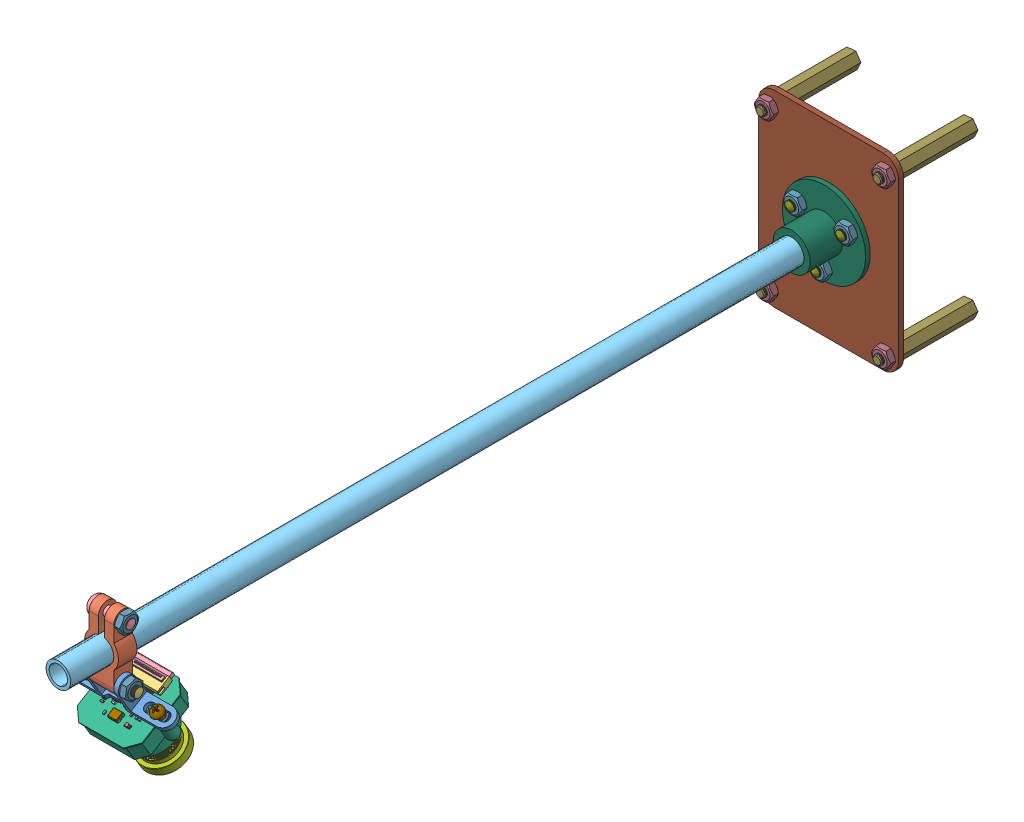
SolidWorks assembly 摄像头装配体, configuration 默认. Lengths in mm.
Overall size (45.45 73.53 276.6).
90 component instances, 34 part files, 64 mates.
Components (placement in the parent):
- 摄像头固定夹-1: 摄像头固定夹 [默认] at (-73.5266 8.9019 124.6716) x (1 0 0) z (0 -0.51597 0.856607) size (34 11.5 6)
- 摄像头支架-1: 摄像头支架 [默认] at (-73.5266 23.6352 128.6271) x (0 -1 0) z (0 0 1) size (24 11 6)
- 十字半圆头长螺钉-M3-白色-16MM-1: 十字半圆头长螺钉-M3-白色-16MM [GB_WOOD_SCREWS_TYPE136 M3X8-N] at (-81.3966 14.6352 131.6271) size (17.31 5.8 5.8)
- 十字半圆头长螺钉-M3-白色-2: 十字半圆头长螺钉-M3-白色 [GB_WOOD_SCREWS_TYPE136 M3X8-N] at (-79.8966 32.6352 131.6271) size (13.31 5.8 5.8)
- 碳纤维杆-摄像头主桅-1: 碳纤维杆-摄像头主桅 [默认] at (-73.5266 23.6352 -101.3729) size (8 8 250)
- 摄像头-1: 摄像头 [Default] at (-73.0566 5.2928 126.029) x (1 0 0) z (0 -0.856607 -0.51597) size (26.62 21 25.09)
  - Board摄像头-1: Board摄像头 [默认] at (0 0 -0.3912) size (26.62 21 0.39)
  - Y1摄像头-1: Y1摄像头 [默认] at origin size (3.3 2.6 1.1)
    - XTAL-OSC-3225-1: XTAL-OSC-3225 [默认] at (0.2033 4.7751 -0.3912) x (1 0 0) z (0 0 -1) size (3.3 2.6 1.1)
      - User_Library-ASTX-H11_Pad-1: User_Library-ASTX-H11_Pad [默认] at origin size (3.3 2.6 0.8)
      - User_Library-ASTX-H11_Pad001-1: User_Library-ASTX-H11_Pad001 [默认] at origin size (2.8 2.4 0.24)
      - User_Library-ASTX-H11_Pad002-1: User_Library-ASTX-H11_Pad002 [默认] at origin size (2.7 2.3 0.04)
      - User_Library-ASTX-H11_ComponentPads-1: User_Library-ASTX-H11_ComponentPads [默认] at origin size (3.3 2.59 0.4)
  - U2摄像头-1: U2摄像头 [默认] at origin size (2.8 2.9 1.45)
    - SOT23-5-1: SOT23-5 [默认] at (-2.517 0.4825 -0.3912) x (0 1 0) z (0 0 -1) size (2.9 2.8 1.45)
  - U1摄像头-1: U1摄像头 [默认] at origin size (11.45 11.44 2.21)
    - CLCC-48-11.43x11.43mm-1: CLCC-48-11.43x11.43mm [默认] at (-0.0237 0.0119 0) x (-1 0 0) z (0 0 1) size (11.45 11.44 2.21)
  - R4摄像头-1: R4摄像头 [默认] at origin size (1 0.5 0.36)
    - RES-0402-1: RES-0402 [默认] at (-5.6286 2.5399 -0.5612) x (0 -1 0) z (1 0 0) size (0.5 0.36 1)
  - R3摄像头-1: R3摄像头 [默认] at origin size (1 0.5 0.36)
    - RES-0402-1: RES-0402 [默认] at (-5.6286 3.4543 -0.5612) x (0 -1 0) z (1 0 0) size (0.5 0.36 1)
  - R2摄像头-1: R2摄像头 [默认] at origin size (0.5 1 0.36)
    - RES-0402-1: RES-0402 [默认] at (3.4035 2.7072 -0.5612) x (-1 0 0) z (0 -1 0) size (0.5 0.36 1)
  - R1摄像头-1: R1摄像头 [默认] at origin size (1 0.5 0.36)
    - RES-0402-1: RES-0402 [默认] at (5.5524 -2.6923 -0.5612) x (0 1 0) z (-1 0 0) size (0.5 0.36 1)
  - L2摄像头-1: L2摄像头 [默认] at origin size (1 0.6 0.5)
    - Chip_Inductor-0402_100505-1: Chip_Inductor-0402_100505 [默认] at (2.7686 0.7112 -0.6312) x (1 0 0) z (0 0 -1) size (1 0.6 0.5)
  - L1摄像头-1: L1摄像头 [默认] at origin size (1 0.6 0.5)
    - Chip_Inductor-0402_100505-1: Chip_Inductor-0402_100505 [默认] at (2.7686 -0.1778 -0.6312) x (1 0 0) z (0 0 -1) size (1 0.6 0.5)
  - D1摄像头-1: D1摄像头 [默认] at origin size (1.7 0.9 0.9)
    - LED-BLUE-0603-1: LED-BLUE-0603 [默认] at (4.4957 5.5045 -0.3912) x (0 1 0) z (0 0 -1) size (0.9 1.7 0.9)
      - User_Library-LTST-C190TBKT_Pad-1: User_Library-LTST-C190TBKT_Pad [默认] at origin size (0.9 1.7 0.28)
      - User_Library-LTST-C190TBKT_Pad005-1: User_Library-LTST-C190TBKT_Pad005 [默认] at origin size (0.35 0.15 0.31)
      - User_Library-LTST-C190TBKT_Pad001-1: User_Library-LTST-C190TBKT_Pad001 [默认] at origin size (0.9 1.7 0.01)
      - User_Library-LTST-C190TBKT_Pad004-1: User_Library-LTST-C190TBKT_Pad004 [默认] at origin size (0.35 0.15 0.31)
      - User_Library-LTST-C190TBKT_Pad003-1: User_Library-LTST-C190TBKT_Pad003 [默认] at origin size (0.8 1.7 0.02)
      - User_Library-LTST-C190TBKT_Lens-1: User_Library-LTST-C190TBKT_Lens [默认] at origin size (0.9 1.15 0.6)
  - CN1摄像头-1: CN1摄像头 [默认] at origin size (13.1 6.5 2.25)
    - FPC-ZIF-SMD-Horizontal-0.5-18-1: FPC-ZIF-SMD-Horizontal-0.5-18 [默认] at (-0.0001 -9.0679 -0.3912) x (-1 0 0) z (0 -1 0) size (13.1 2.25 5.2)
    - FPC-ZIF-SMD-Horizontal-0.5-18_2-1: FPC-ZIF-SMD-Horizontal-0.5-18_2 [默认] at (-0.0001 -9.0679 -0.3912) x (-1 0 0) z (0 -1 0) size (13.1 1.2 2.95)
  - C11摄像头-1: C11摄像头 [默认] at origin size (0.5 1 0.5)
    - CAP-0402-1: CAP-0402 [默认] at (-0.1015 0.0381 -0.6312) x (0 -1 0) z (1 0 0) size (1 0.5 0.5)
  - C10摄像头-1: C10摄像头 [默认] at origin size (1 0.5 0.5)
    - CAP-0402-1: CAP-0402 [默认] at (-2.7305 2.6923 -0.6312) x (-1 0 0) z (0 -1 0) size (1 0.5 0.5)
  - C9摄像头-1: C9摄像头 [默认] at origin size (0.5 1 0.5)
    - CAP-0402-1: CAP-0402 [默认] at (5.8421 -0.0889 -0.6312) x (0 -1 0) z (1 0 0) size (1 0.5 0.5)
  - C8摄像头-1: C8摄像头 [默认] at origin size (0.5 1 0.5)
    - CAP-0402-1: CAP-0402 [默认] at (4.8261 -0.0889 -0.6312) x (0 -1 0) z (1 0 0) size (1 0.5 0.5)
  - C7摄像头-1: C7摄像头 [默认] at origin size (0.5 1 0.5)
    - CAP-0402-1: CAP-0402 [默认] at (0.8383 0.0381 -0.6312) x (0 -1 0) z (1 0 0) size (1 0.5 0.5)
  - C6摄像头-1: C6摄像头 [默认] at origin size (0.5 1 0.5)
    - CAP-0402-1: CAP-0402 [默认] at (-2.7687 5.4737 -0.6312) x (0 1 0) z (-1 0 0) size (1 0.5 0.5)
  - C5摄像头-1: C5摄像头 [默认] at origin size (1 0.5 0.5)
    - CAP-0402-1: CAP-0402 [默认] at (5.5655 -1.5241 -0.6312) x (-1 0 0) z (0 -1 0) size (1 0.5 0.5)
  - C4摄像头-1: C4摄像头 [默认] at origin size (1 0.5 0.5)
    - CAP-0402-1: CAP-0402 [默认] at (0.6731 1.5495 -0.6312) x (1 0 0) z (0 1 0) size (1 0.5 0.5)
  - C3摄像头-1: C3摄像头 [默认] at origin size (0.5 1 0.5)
    - CAP-0402-1: CAP-0402 [默认] at (5.3339 2.6637 -0.6312) x (0 1 0) z (-1 0 0) size (1 0.5 0.5)
  - C2摄像头-1: C2摄像头 [默认] at origin size (0.5 1 0.5)
    - CAP-0402-1: CAP-0402 [默认] at (-5.5373 -0.4445 -0.6312) x (0 1 0) z (-1 0 0) size (1 0.5 0.5)
  - C1摄像头-1: C1摄像头 [默认] at origin size (0.5 1 0.5)
    - CAP-0402-1: CAP-0402 [默认] at (5.8421 2.6543 -0.6312) x (0 -1 0) z (1 0 0) size (1 0.5 0.5)
  - 摄像头-1-1: 摄像头-1 [默认] at (3.1459 -0.8951 -20.4725) size (26.25 20.05 22.5)
    - 底座-1: 底座 [默认] at (-3.1409 0.8701 20.4725) size (26.25 20.05 13.15)
    - 镜头-1: 镜头 [默认] at (-3.1409 0.8701 39.9725) x (0.192959 -0.981207 0) z (0 0 -1) size (14 14 15.3)
    - 螺钉-1: 螺钉 [ISO 7047 - M1.6 x 3 - Z --- 3N] at (-3.1295 -8.8207 30.7429) x (-0.001176 0.999999 0) z (-0.196345 -0.000231 0.980535) size (3.37 3 3)
- 十字半圆头螺钉-M2-1: 十字半圆头螺钉-M2 [GB_WOOD_SCREWS_TYPE136 M2X8-N] at (-61.9266 10.0095 128.8409) x (0 -0.856607 -0.51597) z (1 0 0) size (6.56 3.9 3.9)
- 垫片-M3-1: 垫片-M3 [默认] at (-61.9266 5.6408 126.2095) x (0.716918 0.359712 -0.59719) z (0 0.856607 0.51597) size (4.5 4.5 1)
- 垫片-M3-2: 垫片-M3 [默认] at (-61.9266 7.354 127.2414) x (0.41754 -0.468841 0.778363) z (0 -0.856607 -0.51597) size (4.5 4.5 1)
- 垫片-M3-3: 垫片-M3 [默认] at (-84.1766 6.4974 126.7254) x (0.716918 0.359712 -0.59719) z (0 0.856607 0.51597) size (4.5 4.5 1)
- 十字半圆头螺钉-M2-2: 十字半圆头螺钉-M2 [GB_WOOD_SCREWS_TYPE136 M2X8-N] at (-84.1766 10.0095 128.8409) x (0 -0.856607 -0.51597) z (0.359414 -0.481492 0.799367) size (6.56 3.9 3.9)
- 垫片-M3-4: 垫片-M3 [默认] at (-84.1766 5.6408 126.2095) x (0.716918 0.359712 -0.59719) z (0 0.856607 0.51597) size (4.5 4.5 1)
- 摄像头固定底板-1: 摄像头固定底板 [默认] at (-73.5266 23.6352 -102.9729) x (-1 0 0) z (0 0 1) size (45.45 61 1.6)
- 铜柱_25MM-1: 铜柱_25MM [默认] at (-54.5266 49.1352 -127.9729) size (5.75 5.22 30.08)
- 铜柱_25MM-2: 铜柱_25MM [默认] at (-92.5266 49.1352 -127.9729) size (5.75 5.22 30.08)
- 铜柱_25MM-3: 铜柱_25MM [默认] at (-92.5266 -1.8648 -127.9729) size (5.75 5.22 30.08)
- 铜柱_25MM-4: 铜柱_25MM [默认] at (-54.5266 -1.8648 -127.9729) size (5.75 5.22 30.08)
- 六角螺母-M3-黄色-2: 六角螺母-M3-黄色 [GB_FASTENER_NUT_SNAB1 M3-C] at (-92.5266 49.1352 -98.9729) size (6.35 5.5 2.4)
- 六角螺母-M3-黄色-3: 六角螺母-M3-黄色 [GB_FASTENER_NUT_SNAB1 M3-C] at (-54.5266 49.1352 -98.9729) size (6.35 5.5 2.4)
- 六角螺母-M3-黄色-5: 六角螺母-M3-黄色 [GB_FASTENER_NUT_SNAB1 M3-C] at (-92.5266 -1.8648 -98.9729) size (6.35 5.5 2.4)
- 六角螺母-M3-黄色-6: 六角螺母-M3-黄色 [GB_FASTENER_NUT_SNAB1 M3-C] at (-54.5266 -1.8648 -98.9729) size (6.35 5.5 2.4)
- 六角螺母-M3-白色-6: 六角螺母-M3-白色 [GB_FASTENER_NUT_SNAB1 M3-C] at (-67.1266 32.6352 131.6271) x (0 0 -1) z (1 0 0) size (6.35 5.5 2.4)
- 六角螺母-M3-白色-7: 六角螺母-M3-白色 [GB_FASTENER_NUT_SNAB1 M3-C] at (-65.6266 14.6352 131.6271) x (0 -0.333114 0.942887) z (1 0 0) size (6.35 5.5 2.4)
- 摄像头固定底座-铝制-1: 摄像头固定底座-铝制 [默认] at (-73.5266 23.6352 -101.3729) x (0.5 0.866025 0) z (0 0 1) size (27 27 12)
- 十字半圆头螺钉-M3-白色-8: 十字半圆头螺钉-M3-白色 [GB_WOOD_SCREWS_TYPE136 M3X8-N] at (-65.2994 28.3852 -105.3429) x (0 0 1) z (-0.781973 0.623312 0) size (9.31 5.8 5.8)
- 十字半圆头螺钉-M3-白色-9: 十字半圆头螺钉-M3-白色 [GB_WOOD_SCREWS_TYPE136 M3X8-N] at (-81.7539 28.3852 -105.3429) x (0 0 1) z (-1 0 0) size (9.31 5.8 5.8)
- 十字半圆头螺钉-M3-白色-11: 十字半圆头螺钉-M3-白色 [GB_WOOD_SCREWS_TYPE136 M3X8-N] at (-73.5266 14.1352 -105.3429) x (0 0 1) z (-1 0 0) size (9.31 5.8 5.8)
- 六角螺母-M3-白色-14: 六角螺母-M3-白色 [GB_FASTENER_NUT_SNAB1 M3-C] at (-81.7539 28.3852 -97.4729) size (6.35 5.5 2.4)
- 六角螺母-M3-白色-15: 六角螺母-M3-白色 [GB_FASTENER_NUT_SNAB1 M3-C] at (-65.2994 28.3852 -97.4729) size (6.35 5.5 2.4)
- 六角螺母-M3-白色-16: 六角螺母-M3-白色 [GB_FASTENER_NUT_SNAB1 M3-C] at (-73.5266 14.1352 -97.4729) size (6.35 5.5 2.4)
Mates (geometry in assembly coordinates):
- 同心1: concentric anti-aligned: cylinder of 摄像头固定夹-1 through (-90.5266 14.6352 131.6271) axis (1 0 0) radius 1.5; cylinder of 摄像头支架-1 through (-68.0266 14.6352 131.6271) axis (-1 0 0) radius 1.5
- 重合1: coincident anti-aligned: plane of 摄像头固定夹-1 through (-69.5266 15.6571 135.7449) normal (-1 0 0); plane of 摄像头支架-1 through (-69.5266 11.6352 134.6271) normal (1 0 0)
- 同心31: concentric anti-aligned: cylinder of 摄像头固定夹-1 through (-90.5266 14.6352 131.6271) axis (1 0 0) radius 1.5; cylinder of 十字半圆头长螺钉-M3-白色-16MM-1 through (-95.0259 14.6352 131.6271) axis (-1 0 0) radius 1.5
- 重合31: coincident anti-aligned: plane of 摄像头固定夹-1 through (-79.0266 15.6571 135.7449) normal (-1 0 0); plane of 十字半圆头长螺钉-M3-白色-16MM-1 through (-79.0266 14.6352 130.1271) normal (1 0 0)
- 同心51: concentric aligned: cylinder of 摄像头支架-1 through (-68.0266 32.6352 131.6271) axis (-1 0 0) radius 1.5; cylinder of 十字半圆头长螺钉-M3-白色-2 through (-93.5259 32.6352 131.6271) axis (-1 0 0) radius 1.5
- 重合51: coincident anti-aligned: plane of 摄像头支架-1 through (-77.5266 35.6352 134.6271) normal (-1 0 0); plane of 十字半圆头长螺钉-M3-白色-2 through (-77.5266 32.6352 130.1271) normal (1 0 0)
- 同心7: concentric aligned: cylinder of 摄像头支架-1 through (-73.5266 23.6352 134.6271) axis (0 0 -1) radius 4; cylinder of 碳纤维杆-摄像头主桅-1 through (-73.5266 23.6352 148.6271) axis (0 0 -1) radius 4
- 距离1: distance = 2 mm anti-aligned: plane of 摄像头固定夹-1 through (-90.5266 5.8061 129.8112) normal (0 -0.856607 -0.51597); plane of 摄像头-1/Board摄像头-1 through (-80.3066 11.0456 117.2365) normal (0 0.856607 0.51597)
- 平行1: parallel aligned: plane of 摄像头固定夹-1 through (-73.5266 5.8061 129.8112) normal (0 -0.51597 0.856607); plane of 摄像头-1/Board摄像头-1 through (-65.8066 0.2102 135.2252) normal (0 -0.51597 0.856607)
- 同心62: concentric aligned: cylinder of 摄像头-1/摄像头-1-1/底座-1 through (-61.9266 0.1661 122.9118) axis (0 0.856607 0.51597) radius 2; cylinder of 十字半圆头螺钉-M2-1 through (-61.9266 21.6844 135.8732) axis (0 0.856607 0.51597) radius 1
- 重合62: coincident anti-aligned: plane of 摄像头固定夹-1 through (-56.5266 7.091 130.5852) normal (0 0.856607 0.51597); plane of 十字半圆头螺钉-M2-1 through (-62.9266 8.6389 128.0153) normal (0 -0.856607 -0.51597)
- 距离2: distance = 3 mm anti-aligned: plane of 十字半圆头螺钉-M2-1; plane of 摄像头固定夹-1 through (-73.5266 8.9019 124.6716) normal (0 -0.51597 0.856607)
- 距离3: distance = 5 mm aligned: plane of 摄像头固定夹-1 through (-68.0266 7.091 130.5852) normal (1 0 0); plane of 摄像头-1/摄像头-1-1/底座-1 through (-63.0266 -3.5471 129.0764) normal (1 0 0)
- 同心63: concentric anti-aligned: cylinder of 十字半圆头螺钉-M2-1 through (-61.9266 21.6844 135.8732) axis (0 0.856607 0.51597) radius 1; cylinder of 垫片-M3-1 through (-61.9266 6.4974 126.7254) axis (0 -0.856607 -0.51597) radius 1.5
- 重合65: coincident anti-aligned: plane of 摄像头-1/Board摄像头-1 through (-80.3066 11.0456 117.2365) normal (0 0.856607 0.51597); plane of 垫片-M3-1 through (-61.9266 5.6408 126.2095) normal (0 -0.856607 -0.51597)
- 重合66: coincident anti-aligned: plane of 垫片-M3-1 through (-61.9266 6.4974 126.7254) normal (0 0.856607 0.51597); plane of 垫片-M3-2 through (-61.9266 6.4974 126.7254) normal (0 -0.856607 -0.51597)
- 同心64: concentric aligned: cylinder of 十字半圆头螺钉-M2-1 through (-61.9266 21.6844 135.8732) axis (0 0.856607 0.51597) radius 1; cylinder of 垫片-M3-2 through (-61.9266 6.4974 126.7254) axis (0 0.856607 0.51597) radius 1.5
- 重合67: coincident anti-aligned: plane of 摄像头固定夹-1 through (-79.0266 7.091 130.5852) normal (0 0.856607 0.51597); plane of 十字半圆头螺钉-M2-2 through (-84.5361 9.1204 127.216) normal (0 -0.856607 -0.51597)
- 同心65: concentric anti-aligned: cylinder of 垫片-M3-3 through (-84.1766 7.354 127.2414) axis (0 -0.856607 -0.51597) radius 1.5; cylinder of 十字半圆头螺钉-M2-2 through (-84.1766 21.6844 135.8732) axis (0 0.856607 0.51597) radius 1
- 重合68: coincident anti-aligned: plane of 垫片-M3-3 through (-84.1766 6.4974 126.7254) normal (0 -0.856607 -0.51597); plane of 垫片-M3-4 through (-84.1766 6.4974 126.7254) normal (0 0.856607 0.51597)
- 同心66: concentric aligned: cylinder of 垫片-M3-3 through (-84.1766 7.354 127.2414) axis (0 -0.856607 -0.51597) radius 1.5; cylinder of 垫片-M3-4 through (-84.1766 6.4974 126.7254) axis (0 -0.856607 -0.51597) radius 1.5
- 同心67: concentric aligned: cylinder of 摄像头-1/摄像头-1-1/底座-1 through (-84.1766 0.1661 122.9118) axis (0 0.856607 0.51597) radius 2; cylinder of 十字半圆头螺钉-M2-2 through (-84.1766 21.6844 135.8732) axis (0 0.856607 0.51597) radius 1
- 重合69: coincident anti-aligned: plane of 摄像头-1/Board摄像头-1 through (-80.3066 11.0456 117.2365) normal (0 0.856607 0.51597); plane of 垫片-M3-4 through (-84.1766 5.6408 126.2095) normal (0 -0.856607 -0.51597)
- 重合70: coincident anti-aligned: plane of 摄像头支架-1; plane of 碳纤维杆-摄像头主桅-1 through (-73.5266 23.6352 -101.3729) normal (0 1 0)
- 距离4: distance = 230 mm aligned: plane of 碳纤维杆-摄像头主桅-1 through (-73.5266 23.6352 -101.3729) normal (0 0 -1); plane of 摄像头支架-1 through (-73.5266 23.6352 128.6271) normal (0 0 -1)
- 重合74: coincident anti-aligned: plane of 摄像头固定底板-1 through (-73.5266 23.6352 -102.9729) normal (0 0 -1); plane of 铜柱_25MM-1 through (-54.5266 49.1352 -102.9729) normal (0 0 1)
- 同心71: concentric aligned: cylinder of 摄像头固定底板-1 through (-54.5266 49.1352 -101.3729) axis (0 0 -1) radius 1.5; cylinder of 铜柱_25MM-1 through (-54.5266 49.1352 -97.9729) axis (0 0 -1) radius 1.5
- 重合75: coincident anti-aligned: plane of 摄像头固定底板-1 through (-73.5266 23.6352 -102.9729) normal (0 0 -1); plane of 铜柱_25MM-2 through (-92.5266 49.1352 -102.9729) normal (0 0 1)
- 同心72: concentric aligned: cylinder of 摄像头固定底板-1 through (-92.5266 49.1352 -101.3729) axis (0 0 -1) radius 1.5; cylinder of 铜柱_25MM-2 through (-92.5266 49.1352 -97.9729) axis (0 0 -1) radius 1.5
- 重合76: coincident anti-aligned: plane of 摄像头固定底板-1 through (-73.5266 23.6352 -102.9729) normal (0 0 -1); plane of 铜柱_25MM-3 through (-92.5266 -1.8648 -102.9729) normal (0 0 1)
- 同心73: concentric aligned: cylinder of 摄像头固定底板-1 through (-92.5266 -1.8648 -101.3729) axis (0 0 -1) radius 1.5; cylinder of 铜柱_25MM-3 through (-92.5266 -1.8648 -97.9729) axis (0 0 -1) radius 1.5
- 重合77: coincident anti-aligned: plane of 摄像头固定底板-1 through (-73.5266 23.6352 -102.9729) normal (0 0 -1); plane of 铜柱_25MM-4 through (-54.5266 -1.8648 -102.9729) normal (0 0 1)
- 同心74: concentric aligned: cylinder of 摄像头固定底板-1 through (-54.5266 -1.8648 -101.3729) axis (0 0 -1) radius 1.5; cylinder of 铜柱_25MM-4 through (-54.5266 -1.8648 -97.9729) axis (0 0 -1) radius 1.5
- 同心751: concentric anti-aligned: cylinder of 摄像头固定底板-1 through (-92.5266 49.1352 -101.3729) axis (0 0 -1) radius 1.5; cone of 六角螺母-M3-黄色-2 through (-92.5266 49.1352 -101.3729) axis (0 0 1)
- 重合781: coincident anti-aligned: plane of 摄像头固定底板-1 through (-73.5266 23.6352 -101.3729) normal (0 0 1); plane of 六角螺母-M3-黄色-2 through (-89.3512 49.1352 -101.3729) normal (0 0 -1)
- 同心761: concentric anti-aligned: cylinder of 摄像头固定底板-1 through (-54.5266 49.1352 -101.3729) axis (0 0 -1) radius 1.5; cone of 六角螺母-M3-黄色-3 through (-54.5266 49.1352 -101.3729) axis (0 0 1)
- 重合791: coincident anti-aligned: plane of 摄像头固定底板-1 through (-73.5266 23.6352 -101.3729) normal (0 0 1); plane of 六角螺母-M3-黄色-3 through (-51.3512 49.1352 -101.3729) normal (0 0 -1)
- 同心781: concentric anti-aligned: cylinder of 摄像头固定底板-1 through (-92.5266 -1.8648 -101.3729) axis (0 0 -1) radius 1.5; cone of 六角螺母-M3-黄色-5 through (-92.5266 -1.8648 -101.3729) axis (0 0 1)
- 重合811: coincident anti-aligned: plane of 摄像头固定底板-1 through (-73.5266 23.6352 -101.3729) normal (0 0 1); plane of 六角螺母-M3-黄色-5 through (-89.3512 -1.8648 -101.3729) normal (0 0 -1)
- 同心791: concentric anti-aligned: cylinder of 摄像头固定底板-1 through (-54.5266 -1.8648 -101.3729) axis (0 0 -1) radius 1.5; cone of 六角螺母-M3-黄色-6 through (-54.5266 -1.8648 -101.3729) axis (0 0 1)
- 重合821: coincident anti-aligned: plane of 摄像头固定底板-1 through (-73.5266 23.6352 -101.3729) normal (0 0 1); plane of 六角螺母-M3-黄色-6 through (-51.3512 -1.8648 -101.3729) normal (0 0 -1)
- 同心7921: concentric anti-aligned: cylinder of 摄像头支架-1 through (-68.0266 32.6352 131.6271) axis (-1 0 0) radius 1.5; cone of 六角螺母-M3-白色-6 through (-69.5266 32.6352 131.6271) axis (1 0 0)
- 重合8221: coincident anti-aligned: plane of 摄像头支架-1 through (-69.5266 35.6352 134.6271) normal (1 0 0); plane of 六角螺母-M3-白色-6 through (-69.5266 32.6352 128.4517) normal (-1 0 0)
- 同心7931: concentric aligned: cylinder of 摄像头固定夹-1 through (-90.5266 14.6352 131.6271) axis (1 0 0) radius 3; cone of 六角螺母-M3-白色-7 through (-68.0266 14.6352 131.6271) axis (1 0 0)
- 重合8231: coincident anti-aligned: plane of 摄像头固定夹-1 through (-68.0266 7.091 130.5852) normal (1 0 0); plane of 六角螺母-M3-白色-7 through (-68.0266 13.5774 134.6212) normal (-1 0 0)
- 同心7932: concentric aligned: circle of 摄像头固定底板-1; circle of 摄像头固定底座-铝制-1
- 同心7933: concentric anti-aligned: circle of 摄像头固定底板-1; cylinder of 摄像头固定底座-铝制-1 through (-81.7539 28.3852 -99.8729) axis (0 0 -1) radius 1.5
- 重合8234: coincident anti-aligned: plane of 摄像头固定底板-1 through (-73.5266 23.6352 -101.3729) normal (0 0 1); plane of 摄像头固定底座-铝制-1 through (-73.5266 23.6352 -101.3729) normal (0 0 -1)
- 同心7936: concentric aligned: cylinder of 碳纤维杆-摄像头主桅-1 through (-73.5266 23.6352 148.6271) axis (0 0 -1) radius 4; cylinder of 摄像头固定底座-铝制-1 through (-73.5266 23.6352 -99.8729) axis (0 0 -1) radius 4
- 重合8235: coincident anti-aligned: plane of 碳纤维杆-摄像头主桅-1 through (-73.5266 23.6352 -101.3729) normal (0 0 -1); plane of 摄像头固定底板-1 through (-73.5266 23.6352 -101.3729) normal (0 0 1)
- 同心7937: concentric aligned: cylinder of 摄像头固定底板-1 through (-65.2994 28.3852 -101.3729) axis (0 0 -1) radius 1.5; cylinder of 摄像头固定底座-铝制-1 through (-65.2994 28.3852 -99.8729) axis (0 0 -1) radius 1.5
- 同心79431: concentric aligned: cylinder of 摄像头固定底板-1 through (-65.2994 28.3852 -101.3729) axis (0 0 -1) radius 1.5; cylinder of 十字半圆头螺钉-M3-白色-8 through (-65.2994 28.3852 -118.9721) axis (0 0 -1) radius 1.5
- 重合82411: coincident anti-aligned: plane of 摄像头固定底板-1 through (-73.5266 23.6352 -102.9729) normal (0 0 -1); plane of 十字半圆头螺钉-M3-白色-8 through (-64.1264 27.4502 -102.9729) normal (0 0 1)
- 同心79441: concentric aligned: cylinder of 摄像头固定底板-1 through (-81.7539 28.3852 -101.3729) axis (0 0 -1) radius 1.5; cylinder of 十字半圆头螺钉-M3-白色-9 through (-81.7539 28.3852 -118.9721) axis (0 0 -1) radius 1.5
- 重合82421: coincident anti-aligned: plane of 摄像头固定底板-1 through (-73.5266 23.6352 -102.9729) normal (0 0 -1); plane of 十字半圆头螺钉-M3-白色-9 through (-80.2539 28.3852 -102.9729) normal (0 0 1)
- 同心79461: concentric aligned: cylinder of 摄像头固定底板-1 through (-73.5266 14.1352 -101.3729) axis (0 0 -1) radius 1.5; cylinder of 十字半圆头螺钉-M3-白色-11 through (-73.5266 14.1352 -118.9721) axis (0 0 -1) radius 1.5
- 重合82441: coincident anti-aligned: plane of 摄像头固定底板-1 through (-73.5266 23.6352 -102.9729) normal (0 0 -1); plane of 十字半圆头螺钉-M3-白色-11 through (-72.0266 14.1352 -102.9729) normal (0 0 1)
- 同心79471: concentric anti-aligned: cylinder of 摄像头固定底座-铝制-1 through (-81.7539 28.3852 -99.8729) axis (0 0 -1) radius 1.5; cone of 六角螺母-M3-白色-14 through (-81.7539 28.3852 -99.8729) axis (0 0 1)
- 重合82451: coincident anti-aligned: plane of 摄像头固定底座-铝制-1 through (-73.5266 23.6352 -99.8729) normal (0 0 1); plane of 六角螺母-M3-白色-14 through (-78.5785 28.3852 -99.8729) normal (0 0 -1)
- 同心79481: concentric anti-aligned: cylinder of 摄像头固定底座-铝制-1 through (-65.2994 28.3852 -99.8729) axis (0 0 -1) radius 1.5; cone of 六角螺母-M3-白色-15 through (-65.2994 28.3852 -99.8729) axis (0 0 1)
- 重合82461: coincident anti-aligned: plane of 摄像头固定底座-铝制-1 through (-73.5266 23.6352 -99.8729) normal (0 0 1); plane of 六角螺母-M3-白色-15 through (-62.124 28.3852 -99.8729) normal (0 0 -1)
- 同心79491: concentric anti-aligned: cylinder of 摄像头固定底座-铝制-1 through (-73.5266 14.1352 -99.8729) axis (0 0 -1) radius 1.5; cone of 六角螺母-M3-白色-16 through (-73.5266 14.1352 -99.8729) axis (0 0 1)
- 重合82471: coincident anti-aligned: plane of 摄像头固定底座-铝制-1 through (-73.5266 23.6352 -99.8729) normal (0 0 1); plane of 六角螺母-M3-白色-16 through (-70.3512 14.1352 -99.8729) normal (0 0 -1)
- 重合8249: coincident anti-aligned: plane of 摄像头支架-1; plane of 摄像头固定底板-1
